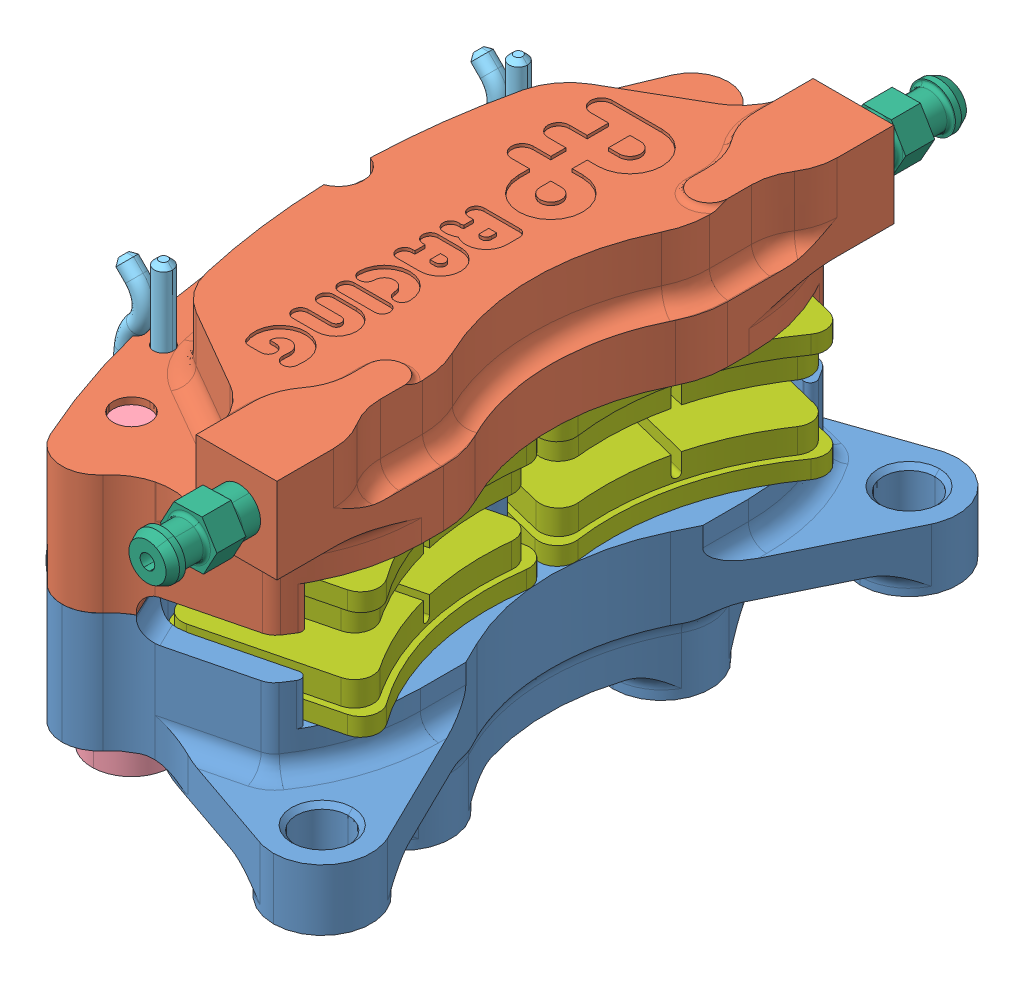
SolidWorks assembly CP4227-2S0, configuration Default. Lengths in mm.
Overall size (71.54 66.42 130.94).
18 component instances, 7 part files, 3 mates.
Components (placement in the parent):
- CP4227-2S0.STEP-1: CP4227-2S0.STEP [Default] x (0 0 -1) z (0 -1 0) size (130.94 71.54 66.42)
  - CP4227-101.STEP-1: CP4227-101.STEP [Default] at origin size (112 60.5 34.68)
  - CP4227-102.STEP-1: CP4227-102.STEP [Default] x (-1 0 0) z (0 0 -1) size (109 47.57 30.98)
  - cp3049-40a_CP4226-103.STEP-1: cp3049-40a_CP4226-103.STEP [Default] at (-23.4668 -94.12 -10.305) size (25.2 25.2 14.87)
  - cp3049-40a_CP4226-103.STEP-2: cp3049-40a_CP4226-103.STEP [Default] at (-23.4668 -94.12 10.305) x (-0.98369 0.179874 0) z (0 0 -1) size (25.2 25.2 14.87)
  - cp3049-40a_CP4226-103.STEP-3: cp3049-40a_CP4226-103.STEP [Default] at (23.4668 -94.12 10.305) x (-0.960147 0.279495 0) z (0 0 -1) size (25.2 25.2 14.87)
  - cp3049-40a_CP4226-103.STEP-4: cp3049-40a_CP4226-103.STEP [Default] at (23.4668 -94.12 -10.305) size (25.2 25.2 14.87)
  - cp3838-M08x1.25m_CP4477-110.STEP-1: cp3838-M08x1.25m_CP4477-110.STEP [Default] at (-41.1 -109.6 19.55) x (-0.998897 0.046962 0) z (0 0 -1) size (13 13 46)
  - cp3838-M08x1.25m_CP4477-110.STEP-2: cp3838-M08x1.25m_CP4477-110.STEP [Default] at (0 -116.83 19.55) x (-0.99038 0.138378 0) z (0 0 -1) size (13 13 46)
  - cp3838-M08x1.25m_CP4477-110.STEP-3: cp3838-M08x1.25m_CP4477-110.STEP [Default] at (41.1 -109.6 19.55) x (-1 -0.000032 0) z (0 0 -1) size (13 13 46)
  - cp4226-104_CP4226-104.STEP-1: cp4226-104_CP4226-104.STEP [Default] at (-29.0318 -116.44 -31.75) x (0 0 1) z (1 0 0) size (61.35 20.1 3)
  - cp4226-104_CP4226-104.STEP-2: cp4226-104_CP4226-104.STEP [Default] at (29.0318 -116.44 -31.75) x (0 0 1) z (1 0 0) size (61.35 20.1 3)
  - CP4469-101.STEP-1: CP4469-101.STEP [Default] at (-65.47 -82.62 -23.98) x (0 0.474307 -0.88036) z (1 0 0) size (9.24 8.21 29.15)
  - CP4469-101.STEP-2: CP4469-101.STEP [Default] at (65.47 -82.62 -23.98) x (0 0.509894 0.860237) z (-1 0 0) size (9.24 8.21 29.15)
  - CP4226-4m.STEP-1: CP4226-4m.STEP [Default] at (10.0433 -40.2815 10.305) x (0.970296 0.241922 0) z (0 0 -1) size (39.7 43.64 7)
  - CP4226-4m.STEP-2: CP4226-4m.STEP [Default] at (10.0433 -40.2815 -10.305) x (-0.970296 -0.241922 0) z (0 0 1) size (39.7 43.64 7)
  - CP4226-4m.STEP-3: CP4226-4m.STEP [Default] at (-10.0433 -40.2815 -10.305) x (-0.970296 0.241922 0) z (0 0 1) size (39.7 43.64 7)
  - CP4226-4m.STEP-4: CP4226-4m.STEP [Default] at (-10.0433 -40.2815 10.305) x (0.970296 -0.241922 0) z (0 0 -1) size (39.7 43.64 7)
Mates (geometry in assembly coordinates):
- Coincident1: coincident anti-aligned: plane of CP4227-2S0.STEP-1 through (0 0 0) normal (0 -1 0)
- Coincident2: coincident aligned: plane of CP4227-2S0.STEP-1 through (0 0 0) normal (1 0 0)
- Coincident3: coincident anti-aligned: plane of CP4227-2S0.STEP-1 through (0 0 0) normal (0 0 -1)
